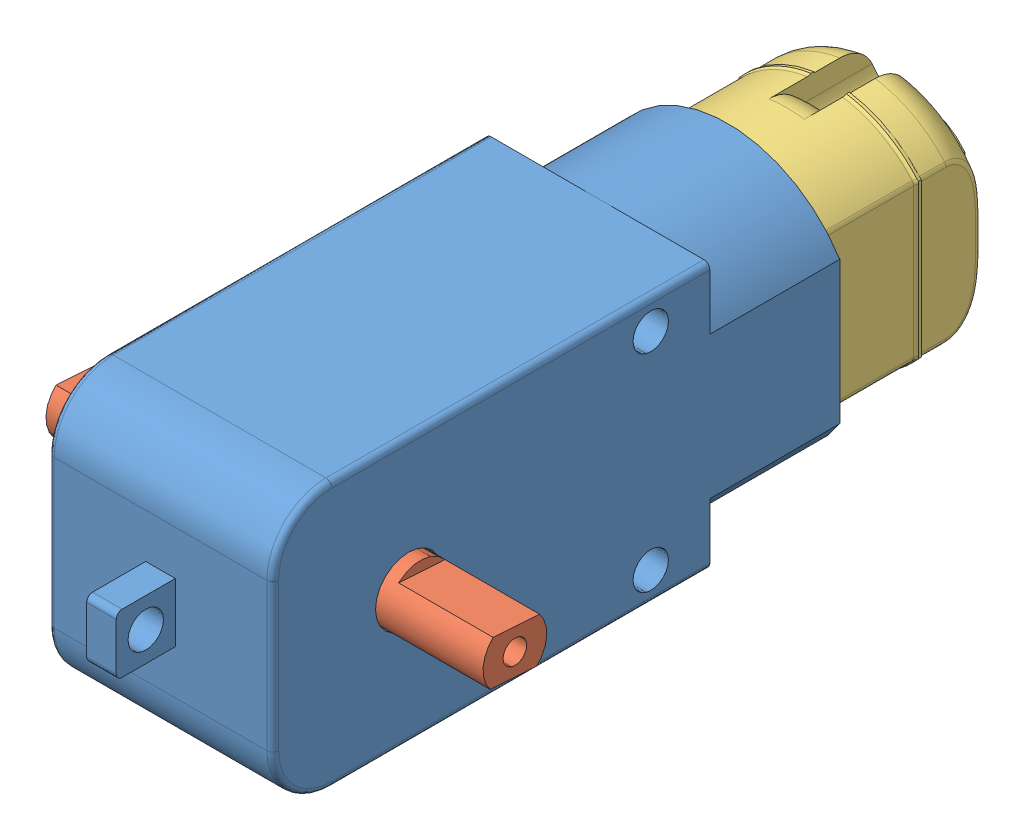
SolidWorks assembly DC Motor Gearbox, configuration Default. Lengths in mm.
Overall size (37 22.5 70).
3 component instances, 3 part files, 11 mates.
Components (placement in the parent):
- Gearbox-1: Gearbox [Default] at (19.5167 31.236 22.8921) size (19 22.5 53)
- output shaft-1: output shaft [Default] at (19.5167 31.236 48.3921) x (1 0 0) z (0 -0.997873 0.065186) size (37 5.4 5.4)
- motor-1: motor [Default] at (19.5167 31.236 -2.1079) size (17.2 19.92 37.8)
Mates (geometry in assembly coordinates):
- Concentric1: concentric: cylinder of Gearbox-1 through (10.0167 31.236 48.3921) axis (1 0 0) radius 2.8; cylinder of output shaft-1 through (38.0167 31.236 48.3921) axis (-1 0 0) radius 2.7
- Coincident2: coincident: plane of Gearbox-1 through (19.5167 31.236 22.8921) normal (1 0 0); plane of output shaft-1 through (19.5167 31.236 48.3921) normal (1 0 0)
- Concentric2: concentric: cylinder of Gearbox-1 through (19.5167 31.236 22.8921) axis (0 0 -1) radius 10.05; cylinder of motor-1 through (19.5167 31.236 22.8921) axis (0 0 -1) radius 9.9
- Parallel1: parallel: plane of Gearbox-1 through (27.8167 36.9028 22.8921) normal (-1 0 0); plane of motor-1 through (27.0167 37.6982 22.8921) normal (1 0 0)
- Coincident3: coincident: plane of Gearbox-1 through (19.5167 31.236 22.8921) normal (0 0 -1); plane of motor-1 through (19.5167 31.236 22.8921) normal (0 0 1)
- Concentric3: concentric: cylinder of output shaft-1 through (38.0167 31.236 48.3921) axis (-1 0 0) radius 2.7; cylinder of ? through (-0.6833 31.236 48.3921) axis (1 0 0) radius 3.25
- Coincident4: coincident: plane of output shaft-1 through (1.0167 31.236 48.3921) normal (-1 0 0); plane of ? through (1.0167 31.236 48.3921) normal (1 0 0)
- Parallel2: parallel: plane of output shaft-1; plane of ? through (-0.6833 34.4651 48.7607) normal (0 -0.623012 -0.782212)
- Parallel3: parallel: plane of output shaft-1 through (30.0167 29.5182 50.4751) normal (0 -0.997873 0.065186); plane of ? through (30.0167 28.7912 46.2508) normal (0 0.997873 -0.065186)
- Concentric4: concentric: cylinder of output shaft-1 through (38.0167 31.236 48.3921) axis (-1 0 0) radius 2.7; cylinder of ? through (30.0167 31.236 48.3921) axis (1 0 0) radius 3.25
- Coincident7: coincident: plane of output shaft-1 through (38.0167 31.236 48.3921) normal (1 0 0); plane of ? through (38.0167 31.236 48.3921) normal (-1 0 0)
